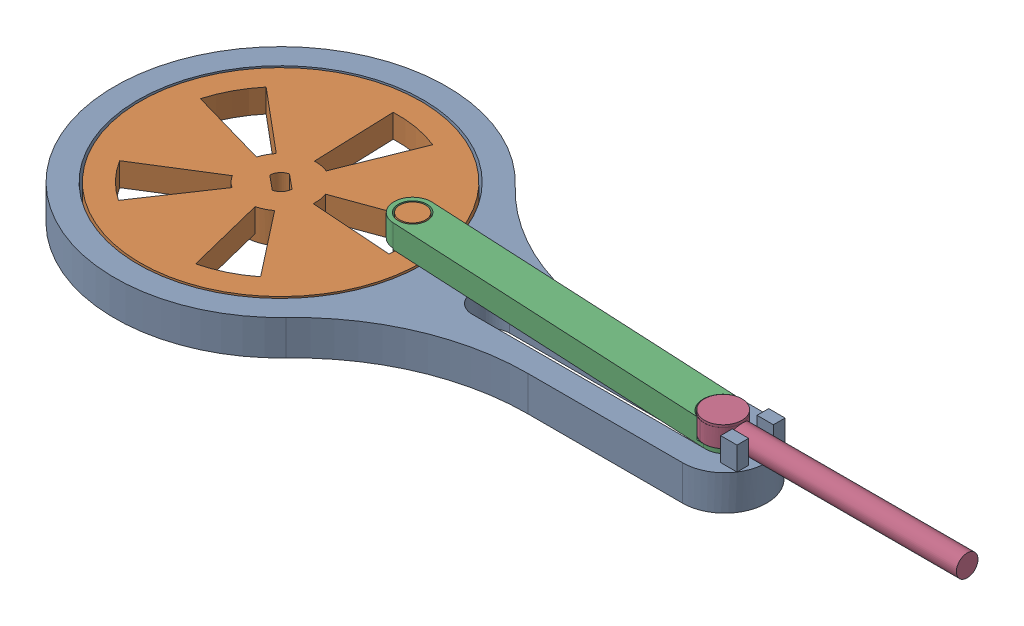
SolidWorks assembly MotorActuatorAssembly, configuration Default. Lengths in mm.
Overall size (186.83 12.68 80.11).
4 component instances, 4 part files, 8 mates.
Components (placement in the parent):
- Chasis-1: Chasis [Default] at origin size (139.5 12.5 71)
- Cog-1: Cog [Default] at (56.7186 0 20.0326) x (0.434541 0 0.900652) z (-0.900652 0 0.434541) size (60 11.56 60)
- Linkage-1: Linkage [Default] at (8.837 0 27.5539) x (0.956169 0 -0.292817) z (0.292817 0 0.956169) size (73.85 12.5 31.81)
- Presser-1: Presser [Default] at (21.228 -0.2 -0.0012) size (56.13 5.2 8.04)
Mates (geometry in assembly coordinates):
- Coincident1: coincident anti-aligned: plane of Chasis-1 through (12.4055 51.6742 55.1864) normal (0 1 0); plane of Linkage-1 through (12.1911 51.6742 50.4422) normal (0 -1 0)
- Coincident2: coincident anti-aligned: plane of Chasis-1 through (12.4055 45.1742 55.1864) normal (0 1 0); plane of Cog-1 through (12.4055 45.1742 55.1864) normal (0 -1 0)
- Concentric1: concentric aligned: cylinder of Cog-1 through (37.1599 56.8891 51.6906) axis (0 1 0) radius 2.75; cylinder of Linkage-1 through (37.1599 56.8891 51.6906) axis (0 1 0) radius 3.0628
- Concentric2: concentric aligned: cylinder of Linkage-1 through (107.0736 56.3914 55.1652) axis (0 -1 0) radius 3.4622; cylinder of Presser-1 through (107.0736 56.0711 55.1652) axis (0 -1 0) radius 3.4622
- Coincident3: coincident anti-aligned: plane of Linkage-1 through (108.4591 52.4499 27.4556) normal (0 1 0); plane of Presser-1 through (114.372 52.4499 28.3982) normal (0 -1 0)
- Tangent3: tangent anti-aligned: plane of Chasis-1 through (12.4055 51.6742 51.1864) normal (0 0 1); cylinder of Linkage-1 through (107.0725 56.6742 55.1864) axis (0 -1 0) radius 4
- Concentric3: concentric aligned: cylinder of Chasis-1 through (12.4055 46.6742 55.1864) axis (0 -1 0) radius 5; circle of Cog-1
- Concentric4: concentric anti-aligned: cylinder of Chasis-1 through (12.4055 51.6742 55.1864) axis (0 -1 0) radius 30.5; cylinder of Cog-1 through (12.4055 46.6742 55.1864) axis (0 1 0) radius 30
